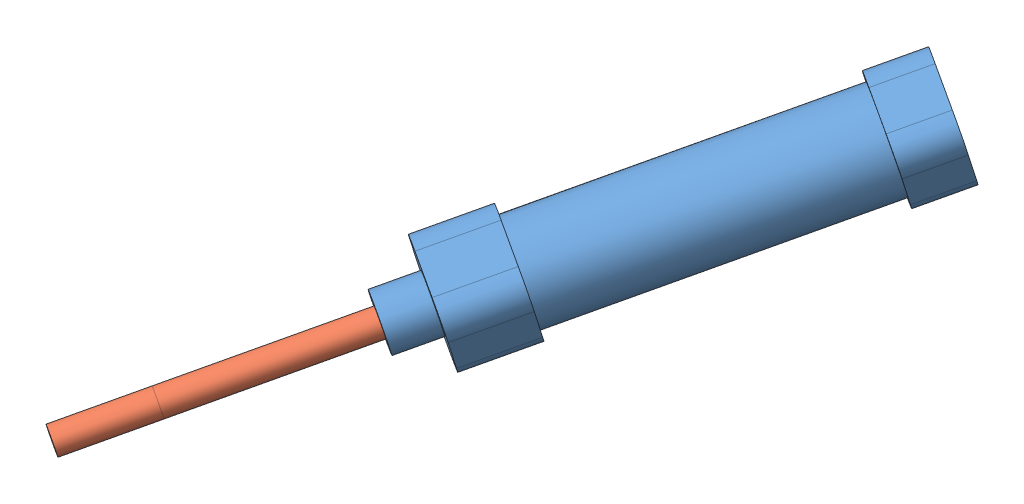
SolidWorks assembly 16x30标准型, configuration 默认. Lengths in mm.
Overall size (82.31 50.39 119.81).
2 component instances, 2 part files, 2 mates.
Components (placement in the parent):
- 16x30标准型壳-1: 16x30标准型壳 [默认] at (36.4935 12.4885 5.4393) x (-0.214003 -0.879112 -0.425869) z (-0.517508 -0.267728 0.812716) size (18 18 86.5)
- 16x30标准型轴-1: 16x30标准型轴 [默认] at (15.7932 1.7794 37.948) x (-0.181371 0.962531 0.20159) z (-0.517508 -0.267728 0.812716) size (5 5 96)
Mates (geometry in assembly coordinates):
- 同心1: concentric anti-aligned: cylinder of 16x30标准型壳-1 through (40.1528 14.3816 -0.3074) axis (-0.517508 -0.267728 0.812716) radius 2.5; cylinder of 16x30标准型轴-1 through (-25.6074 -19.6388 102.9653) axis (0.517508 0.267728 -0.812716) radius 2.5
- LimitDistance1: limit distance = 49.5 mm aligned: plane of 16x30标准型轴-1 through (-33.8875 -23.9225 115.9688) normal (-0.517508 -0.267728 0.812716); plane of 16x30标准型壳-1 through (-8.2709 -10.6699 75.7393) normal (-0.517508 -0.267728 0.812716)
